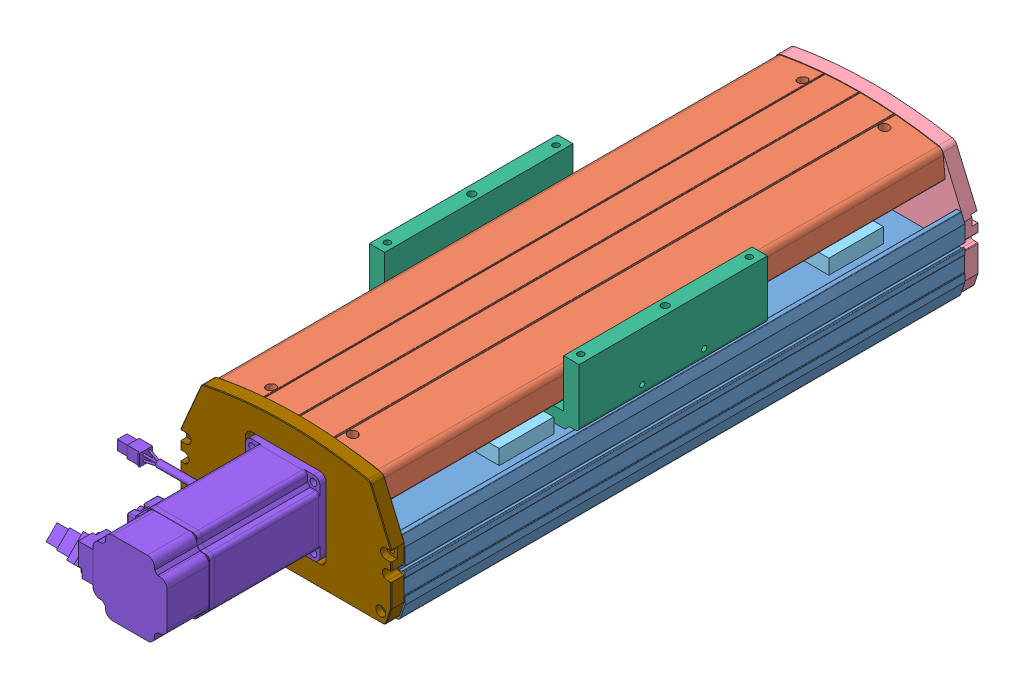
SolidWorks assembly S17M-BC-400W, configuration 默认. Lengths in mm.
Overall size (202.37 123.79 599.71).
13 component instances, 10 part files, 42 mates.
Components (placement in the parent):
- T17-R-011底座^S17M-BC-400W-1: T17-R-011底座^S17M-BC-400W [默认] at origin size (170 60 452) (virtual)
- T17S-L-007上盖^S17M-BC-400W-2: T17S-L-007上盖^S17M-BC-400W [Default] at (0 82 226) size (137.82 27.5 452) (virtual)
- 672 传感器^S17M-BC-400W-1: 672 传感器^S17M-BC-400W [默认] at (-91.7485 42.15 218.8) x (-1 0 0) z (0 0 1) size (13.5 27.4 26.1) (virtual)
- 672 传感器^S17M-BC-400W-2: 672 传感器^S17M-BC-400W [默认] at (-91.7485 42.15 244.9) x (-1 0 0) z (0 0 1) size (13.5 27.4 26.1) (virtual)
- 672 传感器^S17M-BC-400W-3: 672 传感器^S17M-BC-400W [默认] at (-91.7485 42.15 168.35) x (-1 0 0) z (0 0 1) size (13.5 27.4 26.1) (virtual)
- CFT17S-L-001侧面板^S17M-BC-400W-1: CFT17S-L-001侧面板^S17M-BC-400W [默认] at (0 1 -11) size (169 101.5 11) (virtual)
- 复件 滑座S17M^S17M-BC-400W-1: 复件 滑座S17M^S17M-BC-400W [默认] at (0 75.7 53) x (-1 0 0) z (0 1 0) size (144.4 44 43.7) (virtual)
- 复件 滑台S17M^S17M-BC-400W-1: 复件 滑台S17M^S17M-BC-400W [默认] at (0 75.7 159) x (-1 0 0) z (0 1 0) size (169.2 152 78.7) (virtual)
- 复件 滑座S17M^S17M-BC-400W-3: 复件 滑座S17M^S17M-BC-400W [默认] at (0 75.7 319) x (-1 0 0) z (0 1 0) size (144.4 44 43.7) (virtual)
- 外置感应片ST14-17^S17M-BC-400W-1: 外置感应片ST14-17^S17M-BC-400W [默认] at (-85.2 64.1 235) x (0 0 1) z (-1 0 0) size (70 30 7.6) (virtual)
- 400W电机ECMA-C20604RS^S17M-BC-400W-1: 400W电机ECMA-C20604RS^S17M-BC-400W [Default] at (0 49.95 505.35) x (0 1 0) z (-1 0 0) size (94.25 160.75 147.38) (virtual)
- 电机板S17M-BC-60^S17M-BC-400W-1: 电机板S17M-BC-60^S17M-BC-400W [默认] at (-36.7012 39.9909 452) size (170 101.6 11) (virtual)
- 复件 固定座架S17M-P601^S17M-BC-400W-1: 复件 固定座架S17M-P601^S17M-BC-400W [默认] at (-221.8266 42.2 372) size (123 69 10) (virtual)
Mates (geometry in assembly coordinates):
- 重合148: coincident: plane of T17-R-011底座^S17M-BC-400W-1 through (0 0 0) normal (0 0 -1); plane of T17S-L-007上盖^S17M-BC-400W-2 through (66.7465 75.75 0) normal (0 0 -1)
- 重合153: coincident: plane of T17-R-011底座^S17M-BC-400W-1 through (0 0 0) normal (1 0 0); plane of T17S-L-007上盖^S17M-BC-400W-2 through (0 82 226) normal (1 0 0)
- 重合157: coincident: plane of 672 传感器^S17M-BC-400W-1 through (-84.9985 53.25 225.1) normal (1 0 0); plane of 672 传感器^S17M-BC-400W-3 through (-84.9985 53.25 174.65) normal (1 0 0)
- 重合158: coincident: plane of 672 传感器^S17M-BC-400W-1 through (-84.9985 53.25 225.1) normal (1 0 0); plane of 672 传感器^S17M-BC-400W-2 through (-84.9985 53.25 251.2) normal (1 0 0)
- 重合159: coincident: plane of 672 传感器^S17M-BC-400W-1 through (-84.9985 53.25 225.1) normal (0 1 0); plane of 672 传感器^S17M-BC-400W-3 through (-84.9985 53.25 174.65) normal (0 1 0)
- 重合160: coincident: plane of 672 传感器^S17M-BC-400W-1 through (-84.9985 53.25 225.1) normal (0 1 0); plane of 672 传感器^S17M-BC-400W-2 through (-84.9985 53.25 251.2) normal (0 1 0)
- 距离20: distance = 31.55 mm: plane of T17-R-011底座^S17M-BC-400W-1 through (0 -0.5 452) normal (0 -1 0); plane of 672 传感器^S17M-BC-400W-2 through (-84.9985 31.05 251.2) normal (0 -1 0)
- 距离21: distance = 168.35 mm: plane of 672 传感器^S17M-BC-400W-3 through (-98.4985 31.05 168.35) normal (0 0 -1); plane of T17-R-011底座^S17M-BC-400W-1 through (0 0 0) normal (0 0 -1)
- 重合168: coincident: plane of T17-R-011底座^S17M-BC-400W-1 through (-84.9985 0 452) normal (-1 0 0); plane of 672 传感器^S17M-BC-400W-2 through (-84.9985 53.25 251.2) normal (1 0 0)
- 重合169: coincident: plane of 672 传感器^S17M-BC-400W-1 through (-87.9985 34.25 235) normal (0 0 1); plane of 672 传感器^S17M-BC-400W-2 through (-87.9985 34.25 235) normal (0 0 -1)
- 距离22: distance = 206.8 mm: plane of 672 传感器^S17M-BC-400W-2 through (-98.4985 31.05 251.2) normal (0 0 1); plane of T17-R-011底座^S17M-BC-400W-1 through (0 0 452) normal (0 0 1)
- 重合174: coincident: plane of T17-R-011底座^S17M-BC-400W-1 through (0 0 0) normal (0 0 -1); plane of CFT17S-L-001侧面板^S17M-BC-400W-1 through (0.0037 -247.5005 0) normal (0 0 1)
- 重合183: coincident: plane of T17-R-011底座^S17M-BC-400W-1 through (0 0 0) normal (1 0 0); plane of CFT17S-L-001侧面板^S17M-BC-400W-1 through (0 1 -11) normal (1 0 0)
- 距离23: distance = 82.5 mm: plane of T17S-L-007上盖^S17M-BC-400W-2 through (0 82 226) normal (0 1 0); plane of T17-R-011底座^S17M-BC-400W-1 through (0 -0.5 452) normal (0 -1 0)
- 距离26: distance = 1 mm: plane of T17-R-011底座^S17M-BC-400W-1 through (0 0 0) normal (0 1 0); plane of CFT17S-L-001侧面板^S17M-BC-400W-1 through (0 1 -11) normal (0 1 0)
- 重合211: coordinate: point of T17-R-011底座^S17M-BC-400W-1
- 距离27: distance = 110 mm: plane of 复件 滑台S17M^S17M-BC-400W-1 through (-113.7999 109.5 159) normal (0 1 0); plane of T17-R-011底座^S17M-BC-400W-1 through (0 -0.5 452) normal (0 -1 0)
- 宽度1: width: plane of 复件 滑台S17M^S17M-BC-400W-1 through (-84.6 65.3 311) normal (-1 0 0); plane of 复件 滑台S17M^S17M-BC-400W-1 through (84.6 111.2 311) normal (1 0 0); plane of T17-R-011底座^S17M-BC-400W-1 through (84.4985 0 452) normal (1 0 0); plane of T17-R-011底座^S17M-BC-400W-1 through (-84.4985 0 452) normal (-1 0 0)
- 宽度2: width: plane of 复件 滑台S17M^S17M-BC-400W-1 through (-84.6 65.3 311) normal (-1 0 0); plane of 复件 滑台S17M^S17M-BC-400W-1 through (84.6 111.2 311) normal (1 0 0); plane of 复件 滑座S17M^S17M-BC-400W-1 through (72.2 32 97) normal (1 0 0); plane of 复件 滑座S17M^S17M-BC-400W-1 through (-72.2 32 97) normal (-1 0 0)
- 距离29: distance = 5 mm: plane of 复件 滑座S17M^S17M-BC-400W-1 through (40 70.7 97) normal (0 1 0); plane of 复件 滑台S17M^S17M-BC-400W-1 through (-40 75.7 311) normal (0 1 0)
- 重合221: coincident: plane of 复件 滑座S17M^S17M-BC-400W-1 through (-40 75.7 97) normal (0 1 0); plane of 复件 滑座S17M^S17M-BC-400W-3 through (-40 75.7 363) normal (0 1 0)
- 重合222: coincident: plane of 复件 滑座S17M^S17M-BC-400W-1 through (-72.2 32 97) normal (-1 0 0); plane of 复件 滑座S17M^S17M-BC-400W-3 through (-72.2 32 363) normal (-1 0 0)
- 距离30: distance = 8 mm: plane of 复件 滑座S17M^S17M-BC-400W-3 through (81.6 65.3 319) normal (0 0 -1); plane of 复件 滑台S17M^S17M-BC-400W-1 through (81.6 65.3 311) normal (0 0 1)
- 距离31: distance: plane of 复件 滑座S17M^S17M-BC-400W-3 through (81.6 65.3 319) normal (0 0 -1); plane of 复件 滑座S17M^S17M-BC-400W-1 through (81.6 65.3 97) normal (0 0 1)
- 重合223: coincident: plane of 复件 滑台S17M^S17M-BC-400W-1 through (-84.6 65.3 311) normal (-1 0 0); plane of 外置感应片ST14-17^S17M-BC-400W-1 through (-84.6 64.1 235) normal (1 0 0)
- 同心121: concentric: cylinder of 复件 滑台S17M^S17M-BC-400W-1 through (-84.6 70.1 204) axis (-1 0 0) radius 2.1; cylinder of 外置感应片ST14-17^S17M-BC-400W-1 through (-85.2 70.1 204) axis (-1 0 0) radius 2.75
- 同心122: concentric: cylinder of 复件 滑台S17M^S17M-BC-400W-1 through (-84.6 70.1 253.8046) axis (-1 0 0) radius 2.1; cylinder of 外置感应片ST14-17^S17M-BC-400W-1 through (-85.2 70.1 253.8046) axis (-1 0 0) radius 2.75
- LimitDistance1: limit distance = 7.5 mm: line of 672 传感器^S17M-BC-400W-2 through (-87.9985 35.25 235) axis (0 1 0); plane of 外置感应片ST14-17^S17M-BC-400W-1 through (-85.2 62.5 227.5) normal (0 0 -1)
- 重合224: coincident: plane of T17-R-011底座^S17M-BC-400W-1 through (0 0 452) normal (0 0 1); plane of 电机板S17M-BC-60^S17M-BC-400W-1 through (-77.6083 5 452) normal (0 0 -1)
- 重合225: coincident: plane of T17-R-011底座^S17M-BC-400W-1 through (-84.9985 0 452) normal (-1 0 0); plane of 电机板S17M-BC-60^S17M-BC-400W-1 through (-84.9985 55.8992 463) normal (-1 0 0)
- 距离32: distance = 1.5 mm: plane of 电机板S17M-BC-60^S17M-BC-400W-1 through (-77.6083 1 463) normal (0 -1 0); plane of T17-R-011底座^S17M-BC-400W-1 through (0 -0.5 452) normal (0 -1 0)
- 距离33: distance = 5 mm: plane of 电机板S17M-BC-60^S17M-BC-400W-1 through (-77.6083 5 463) normal (0 0 1); plane of 400W电机ECMA-C20604RS^S17M-BC-400W-1 through (-31.0457 18.9043 458) normal (0 0 -1)
- 重合229: coincident: axis of 400W电机ECMA-C20604RS^S17M-BC-400W-1 through (0 49.95 428.5) axis (0 0 1)
- 平行1: parallel: plane of T17-R-011底座^S17M-BC-400W-1 through (0 -0.5 452) normal (0 -1 0); plane of 400W电机ECMA-C20604RS^S17M-BC-400W-1 through (17.68 19.95 552.384) normal (0 -1 0)
- 距离34: distance = 50.45 mm: line of 400W电机ECMA-C20604RS^S17M-BC-400W-1 through (0 49.95 428.5) axis (0 0 1); plane of T17-R-011底座^S17M-BC-400W-1 through (0 -0.5 452) normal (0 -1 0)
- 同心123: concentric: cylinder of 400W电机ECMA-C20604RS^S17M-BC-400W-1 through (0 49.95 429) axis (0 0 1) radius 7; cylinder of 复件 固定座架S17M-P601^S17M-BC-400W-1 through (0 49.95 332.9462) axis (0 0 1) radius 23
- 重合230: coincident: plane of 电机板S17M-BC-60^S17M-BC-400W-1 through (-77.6083 5 452) normal (0 0 -1); plane of 复件 固定座架S17M-P601^S17M-BC-400W-1 through (15.5 80.45 452) normal (0 0 1)
- 平行2: parallel: plane of 400W电机ECMA-C20604RS^S17M-BC-400W-1 through (-17.68 79.95 552.384) normal (0 1 0); plane of 复件 固定座架S17M-P601^S17M-BC-400W-1 through (17.5 82.2 452) normal (0 1 0)
- 距离36: distance = 228 mm: cylinder of 复件 滑台S17M^S17M-BC-400W-1 through (-78 111.2 235) axis (0 1 0) radius 3; plane of 电机板S17M-BC-60^S17M-BC-400W-1 through (-77.6083 5 463) normal (0 0 1)
- 宽度3: width: plane of 672 传感器^S17M-BC-400W-2 through (-98.4985 31.05 244.9) normal (0 0 -1); plane of 672 传感器^S17M-BC-400W-1 through (-98.4985 31.05 225.1) normal (0 0 1); plane of 外置感应片ST14-17^S17M-BC-400W-1 through (-92.2 62.5 242.5) normal (0 0 1); plane of 外置感应片ST14-17^S17M-BC-400W-1 through (-92.2 47.1 227.5) normal (0 0 -1)
- 同心125: concentric: cone of 复件 滑台S17M^S17M-BC-400W-1 through (-73.6 70.1 210) axis (1 0 0); cylinder of 外置感应片ST14-17^S17M-BC-400W-1 through (-85.2 70.1 210) axis (-1 0 0) radius 2.75
- 同心126: concentric: cylinder of 复件 滑台S17M^S17M-BC-400W-1 through (-84.6 70.1 260) axis (-1 0 0) radius 2.1; cylinder of 外置感应片ST14-17^S17M-BC-400W-1 through (-85.2 70.1 260) axis (-1 0 0) radius 2.75
